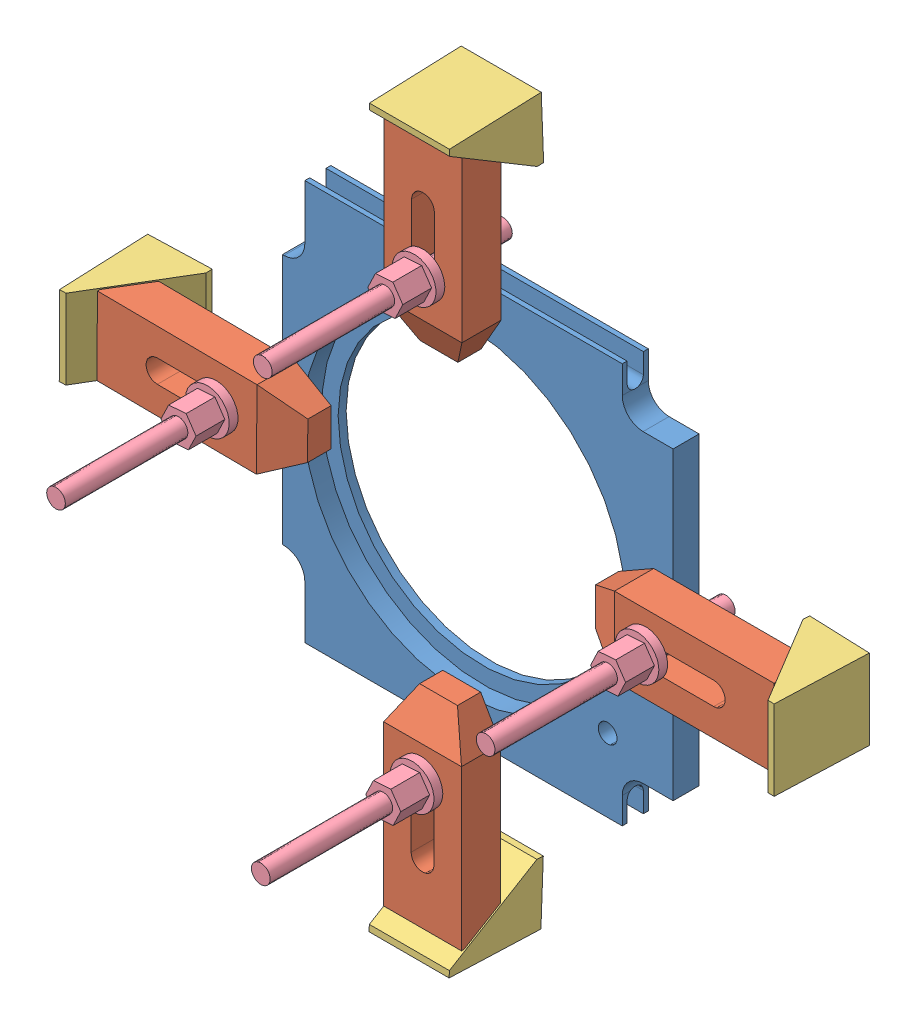
SolidWorks assembly Fixture-undercut-part, configuration All clamps. Lengths in mm.
Overall size (229.08 230.14 78.96).
13 component instances, 4 part files, 8 mates.
Components (placement in the parent):
- Fixture-undercut-part-1: Fixture-undercut-part [Default] at (57.186 0 0) x (0 0 1) z (-1 0 0) size (8.26 127 123.95)
- Short-clamp-toe-2: Short-clamp-toe [Default] at (59.2079 6.7742 10.9361) x (0 1 0) z (0 0 1) size (61.72 24.71 12.45)
- Short-clamp-toe-4: Short-clamp-toe [Default] at (59.2177 -2.1506 11.0836) x (0 -1 0) z (0 0 1) size (61.72 24.71 12.45)
- Short-clamp-wedge-2: Short-clamp-wedge [Default] at (46.6068 0.0427 -5.5453) x (0 0.038151 0.999272) z (1 0 0) size (29.14 19.72 25.4)
- Short-clamp-wedge-3: Short-clamp-wedge [Default] at (72.2619 4.7581 -5.3977) x (0 -0.038151 0.999272) z (-1 0 0) size (29.14 19.72 25.4)
- Short-clamp-bolt-3: Short-clamp-bolt [Default] at (-10.9915 73.142 23.3821) size (13.89 13.89 76.2)
- Short-clamp-bolt-4: Short-clamp-bolt [Default] at (-11.4778 -66.3426 23.5296) size (13.89 13.89 76.2)
- Short-clamp-toe-1: Short-clamp-toe [Default] at (63.63 1.5156 8.3277) size (61.72 24.71 12.45)
- Short-clamp-toe-3: Short-clamp-toe [Default] at (57.6843 1.1605 8.431) x (-0.999962 0.008727 0) z (0 0 1) size (61.72 24.71 12.45)
- Short-clamp-wedge-1: Short-clamp-wedge [Default] at (62.4804 -11.1414 -6.5623) x (-0.038151 0 0.999272) z (0 1 0) size (29.14 19.72 25.4)
- Short-clamp-wedge-4: Short-clamp-wedge [Default] at (58.9859 14.2162 -6.5221) x (0.03812 -0.004212 0.999264) z (-0.006342 -0.999972 -0.003973) size (29.14 19.72 25.4)
- Short-clamp-bolt-1: Short-clamp-bolt [Default] at (-79.0962 1.7202 20.877) size (13.89 13.89 76.2)
- Short-clamp-bolt-2: Short-clamp-bolt [Default] at (57.0997 2.0951 20.7737) size (13.89 13.89 76.2)
Mates (geometry in assembly coordinates):
- Coincident3: coincident anti-aligned: plane of Short-clamp-toe-3 through (-46.7775 -10.2854 20.0702) normal (-0.857411 0.007483 -0.514578); plane of Short-clamp-wedge-4 through (-50.7738 -10.6204 26.724) normal (0.857411 -0.007483 0.514578)
- Coincident4: coincident anti-aligned: plane of Short-clamp-toe-4 through (71.5748 -106.5086 22.7228) normal (0 -0.857444 -0.514578); plane of Short-clamp-wedge-2 through (72.0068 -109.5571 27.8025) normal (0 0.857444 0.514578)
- Coincident5: coincident anti-aligned: plane of Short-clamp-toe-1 through (167.988 13.8727 19.9668) normal (0.857444 0 -0.514578); plane of Short-clamp-wedge-1 through (172.0801 14.2586 26.7855) normal (-0.857444 0 0.514578)
- Coincident6: coincident anti-aligned: plane of Short-clamp-toe-2 through (46.8508 111.1321 22.5752) normal (0 0.857444 -0.514578); plane of Short-clamp-wedge-3 through (46.8619 114.3578 27.9502) normal (0 -0.857444 0.514578)
- Coincident7: coincident anti-aligned: plane of Short-clamp-toe-4 through (59.2177 -2.1506 23.5296) normal (0 0 1); plane of Short-clamp-bolt-4 through (58.6971 -66.3426 23.5296) normal (0 0 -1)
- Coincident8: coincident anti-aligned: plane of Short-clamp-toe-3 through (57.6843 1.1605 20.877) normal (0 0 1); plane of Short-clamp-bolt-1 through (-8.9214 1.7202 20.877) normal (0 0 -1)
- Coincident9: coincident anti-aligned: plane of Short-clamp-toe-2 through (59.2079 6.7742 23.3821) normal (0 0 1); plane of Short-clamp-bolt-3 through (59.1834 73.142 23.3821) normal (0 0 -1)
- Coincident10: coincident anti-aligned: plane of Short-clamp-toe-1 through (63.63 1.5156 20.7737) normal (0 0 1); plane of Short-clamp-bolt-2 through (127.2745 2.0951 20.7737) normal (0 0 -1)
